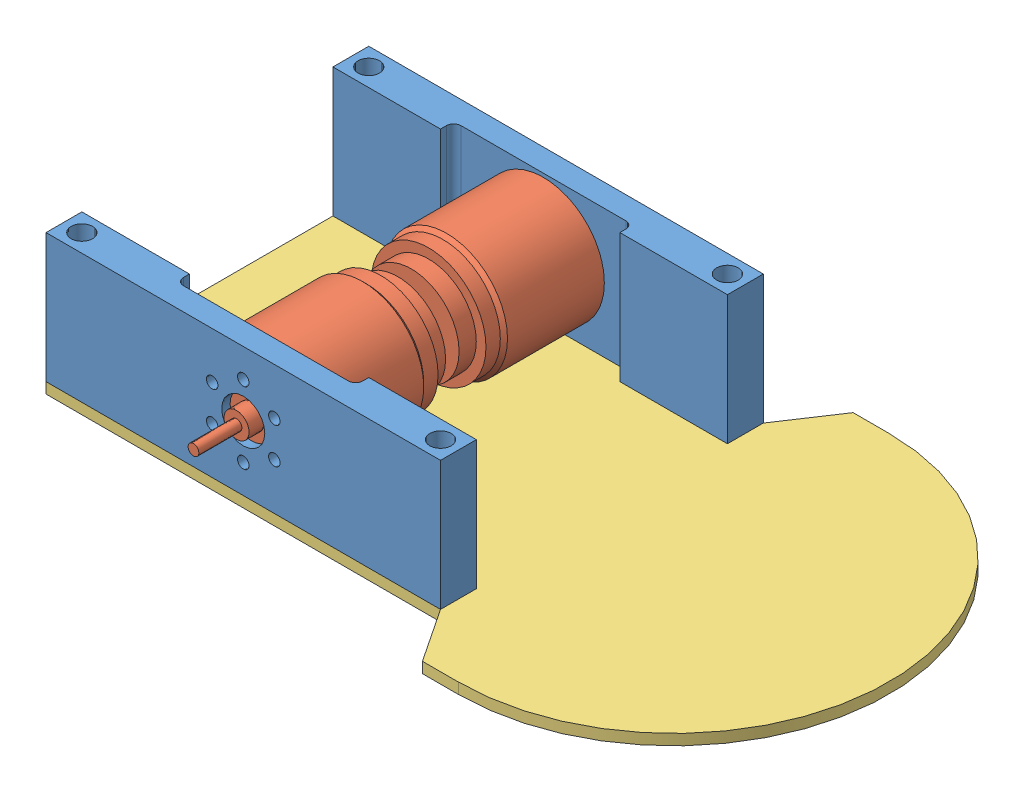
SolidWorks assembly assembly, configuration Default. Lengths in mm.
Overall size (95.02 19.5 60.04).
6 component instances, 4 part files, 9 mates.
Components (placement in the parent):
- motormount-1: motormount [Default] at (11.0977 -5.5209 13.6293) size (55 18 5)
- 1717SR-1: 1717SR [Default] at (-35.3425 3.4791 12.6293) x (-1 0 0) z (0 0 1) size (17 17 28.5)
- base-1: base [Default] at (-40.3425 -7.0209 47.9683) x (0 0 1) z (-1 0 0) size (60.04 1.5 95.02)
- motormount-2: motormount [Default] at (-81.7827 -5.5209 52.3073) x (-1 0 0) z (0 0 -1) size (55 18 5)
- 1717SR-2: 1717SR [Default] at (-35.3425 3.4791 53.3073) x (-1 0 0) z (0 0 -1) size (17 17 28.5)
- perfboard-1: perfboard [Default] at (-62.8425 12.4791 60.4683) x (0 0 -1) z (1 0 0) size (50 1 55) (hidden)
Mates (geometry in assembly coordinates):
- Coincident7: coincident anti-aligned: circle of motormount-1; circle of 1717SR-1
- Coincident8: coincident anti-aligned: circle of motormount-1; circle of 1717SR-1
- Coincident9: coincident aligned: circle of motormount-1; circle of base-1
- Coincident10: coincident aligned: circle of motormount-1; circle of base-1
- Coincident11: coincident anti-aligned: circle of motormount-2; circle of 1717SR-2
- Coincident14: coincident aligned: circle of motormount-1; circle of perfboard-1
- Coincident16: coincident anti-aligned: circle of motormount-2; circle of 1717SR-2
- Coincident19: coincident aligned: circle of base-1; circle of motormount-2
- Coincident20: coincident aligned: circle of base-1; circle of motormount-2
